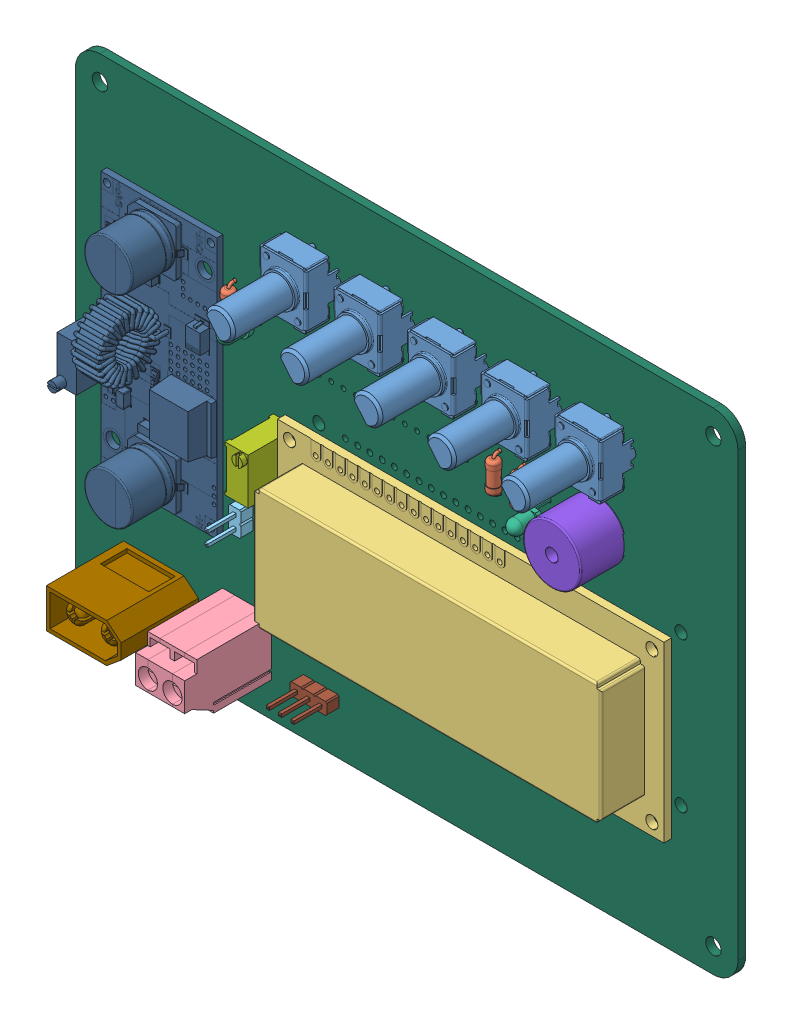
SolidWorks assembly SPEED CONTROL MOTOR DC, configuration Default. Lengths in mm.
Overall size (137.16 101.6 38.13).
45 component instances, 15 part files, 0 mates.
Components (placement in the parent):
- R-0904N-L-20F-green-1: R-0904N-L-20F-green [Default] at (141.184 -41.768 1.65) x (-1 0 0) z (0 0 1) size (11.32 12.6 23.8)
  - COMPOUND-1: COMPOUND [Default] at origin size (11.32 12.6 23.8)
- R_Axial_DIN0207_L6.3mm_D2.5mm_P7.62mm_Horizontal-1: R_Axial_DIN0207_L6.3mm_D2.5mm_P7.62mm_Horizontal [Default] at (63.5 -52.07 1.65) x (0 -1 0) z (0 0 1) size (8.22 2.5 5.5)
  - SOLID-1: SOLID [Default] at origin size (8.22 2.5 5.5)
- R_Axial_DIN0207_L6.3mm_D2.5mm_P7.62mm_Horizontal-2: R_Axial_DIN0207_L6.3mm_D2.5mm_P7.62mm_Horizontal [Default] at (118.364 -55.118 1.65) x (0 -1 0) z (0 0 1) size (8.22 2.5 5.5)
  - SOLID-1: SOLID [Default] at origin size (8.22 2.5 5.5)
- WC1602A-1: WC1602A [Default] at (86.364 -68.9705 1.65) size (80 36 15)
  - SOLID_2-1: SOLID_2 [Default] at origin size (80 36 15)
- 691236510002 (rev1)-1: 691236510002 (rev1) [Default] at (61 -119.8 1.65) x (0 1 0) z (1 0 0) size (11.35 22 10.76)
  - COMPOUND_2-1: COMPOUND_2 [Default] at origin size (11.35 22 10.76)
- PinHeader_1x02_P2.54mm_Vertical-1: PinHeader_1x02_P2.54mm_Vertical [Default] at (66.04 -91.44 1.65) size (2.54 5.08 11.54)
  - SOLID_3-1: SOLID_3 [Default] at origin size (2.54 5.08 11.54)
- LED_D3.0mm-1: LED_D3.0mm [Default] at (68.58 -54.61 1.65) x (0 -1 0) z (0 0 1) size (3.4 3.8 10.8)
  - SOLID_4-1: SOLID_4 [Default] at origin size (3.4 3.8 10.8)
- Potentiometer_Bourns_3296W_Vertical-1: Potentiometer_Bourns_3296W_Vertical [Default] at (73.914 -74.168 1.65) x (0 1 0) z (0 0 1) size (9.53 4.83 17.07)
  - SOLID_5-1: SOLID_5 [Default] at origin size (9.53 4.83 17.07)
- MagneticBuzzer_ProSignal_ABI-009-RC-1: MagneticBuzzer_ProSignal_ABI-009-RC [Default] at (138.684 -62.728 1.65) x (0 1 0) z (0 0 1) size (12 12 12.53)
  - SOLID_6-1: SOLID_6 [Default] at origin size (12 12 12.53)
- AMASS_XT60-M_1x02_P7.2mm_Vertical-1: AMASS_XT60-M_1x02_P7.2mm_Vertical [Default] at (51.86 -114.3 1.65) x (-1 0 0) z (0 0 1) size (15.9 8.1 20.5)
  - COMPOUND_3-1: COMPOUND_3 [Default] at origin size (15.9 8.1 20.5)
- R-0904N-L-20F-green-2: R-0904N-L-20F-green [Default] at (95.464 -41.768 1.65) x (-1 0 0) z (0 0 1) size (11.32 12.6 23.8)
  - COMPOUND-1: COMPOUND [Default] at origin size (11.32 12.6 23.8)
- R_Axial_DIN0207_L6.3mm_D2.5mm_P7.62mm_Horizontal-3: R_Axial_DIN0207_L6.3mm_D2.5mm_P7.62mm_Horizontal [Default] at (123.444 -55.118 1.65) x (0 -1 0) z (0 0 1) size (8.22 2.5 5.5)
  - SOLID-1: SOLID [Default] at origin size (8.22 2.5 5.5)
- R-0904N-L-20F-green-3: R-0904N-L-20F-green [Default] at (125.944 -41.768 1.65) x (-1 0 0) z (0 0 1) size (11.32 12.6 23.8)
  - COMPOUND-1: COMPOUND [Default] at origin size (11.32 12.6 23.8)
- R-0904N-L-20F-green-4: R-0904N-L-20F-green [Default] at (80.184 -41.768 1.65) x (-1 0 0) z (0 0 1) size (11.32 12.6 23.8)
  - COMPOUND-1: COMPOUND [Default] at origin size (11.32 12.6 23.8)
- LED_D3.0mm-2: LED_D3.0mm [Default] at (128.524 -58.928 1.65) x (0 -1 0) z (0 0 1) size (3.4 3.8 10.8)
  - SOLID_4-1: SOLID_4 [Default] at origin size (3.4 3.8 10.8)
- XL4015_MODELO_PISTAS-1: XL4015_MODELO_PISTAS [Default] at (48.26 -71.12 -52.35) x (0 1 0) z (0 0 1) size (54.01 24.02 14.75)
  - COMPOUND_4-1: COMPOUND_4 [Default] at origin size (54.01 24.02 14.75)
- R-0904N-L-20F-green-5: R-0904N-L-20F-green [Default] at (110.704 -41.768 1.65) x (-1 0 0) z (0 0 1) size (11.32 12.6 23.8)
  - COMPOUND-1: COMPOUND [Default] at origin size (11.32 12.6 23.8)
- PinHeader_1x03_P2.54mm_Vertical-1: PinHeader_1x03_P2.54mm_Vertical [Default] at (78.755 -116.84 1.65) x (0 1 0) z (0 0 1) size (2.54 7.62 11.54)
  - SOLID_7-1: SOLID_7 [Default] at origin size (2.54 7.62 11.54)
- D_SMB-1: D_SMB [Default] at (53.34 -38.1 -0.05) x (1 0 0) z (0 0 -1) size (5.3 3.55 2.15)
  - SOLID_8-1: SOLID_8 [Default] at origin size (5.3 3.55 2.15)
- SOIC-8_3.9x4.9mm_P1.27mm-1: SOIC-8_3.9x4.9mm_P1.27mm [Default] at (66.04 -101.6 -0.05) x (0 1 0) z (0 0 -1) size (6 4.9 1.75)
  - SOLID_9-1: SOLID_9 [Default] at origin size (6 4.9 1.75)
- arduino1-1: arduino1 [Default] at (98.879 -84.698 -12.55) x (1 0 0) z (0 -1 0) size (75.6 16.19 53.3)
  - COMPOUND_5-1: COMPOUND_5 [Default] at origin size (75.6 16.19 53.3)
- D_SMB-2: D_SMB [Default] at (53.34 -104.14 -0.05) x (-1 0 0) z (0 0 -1) size (5.3 3.55 2.15)
  - SOLID_8-1: SOLID_8 [Default] at origin size (5.3 3.55 2.15)
- _autosave-SPEED_CONTROL PCB-1: _autosave-SPEED_CONTROL PCB [Default] at origin size (137.16 101.6 1.6)
